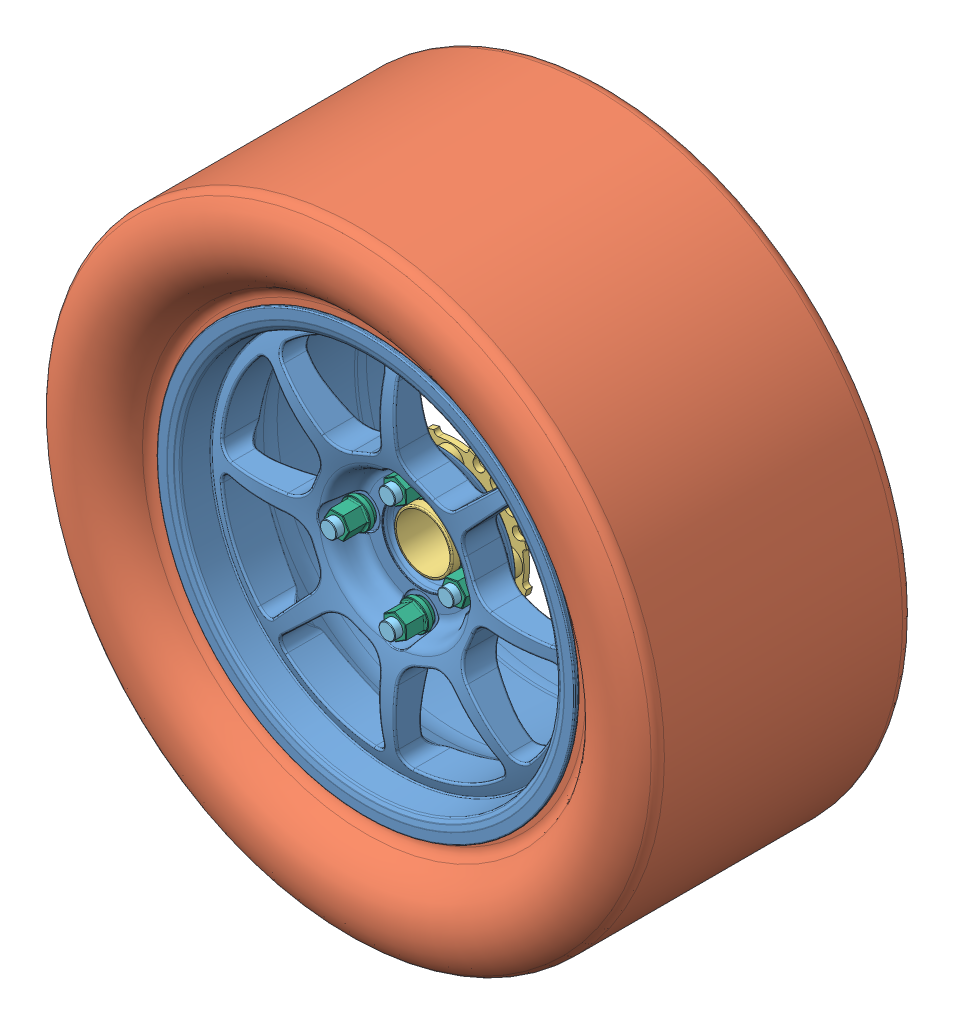
SolidWorks assembly PUTM-S-SR-WT-Hub_Assembly, configuration Default. Lengths in mm.
Overall size (534.5 534.5 238.76).
12 component instances, 6 part files, 26 mates.
Components (placement in the parent):
- PUTM-S-WT-Wheel_Rim-1: PUTM-S-WT-Wheel_Rim [Domyślna] at (27.2371 -11.0021 -114.5898) x (0 0 -1) z (1 0.000237 0) size (189.8 356.77 356.77)
- PUTM-S-SR-WT-Tire-1: PUTM-S-SR-WT-Tire [Default] at (27.2371 -11.0021 -144.4518) x (0.999763 0.021752 0) z (0.021752 -0.999763 0) size (523.24 238.76 523.24)
- PUTM-S-SR-WT-Hub-1: PUTM-S-SR-WT-Hub [Domyślna] at (27.2371 -11.0021 -98.5898) x (0.000237 -1 0) z (0 0 1) size (128.55 128.55 119.65)
- PUTM-S-SR-WT-WH-tripod_housing_2mm-1: PUTM-S-SR-WT-WH-tripod_housing_2mm [Domyślna] at (27.2371 -11.0021 -197.7398) x (-0.999996 0.00292 0) z (0.00292 0.999996 0) size (55.96 51.5 61.23)
- PUTM-S-SF-WT-WH-wheel_stud-1: PUTM-S-SF-WT-WH-wheel_stud [Domyślna] at (-22.7629 -11.014 -129.5898) x (0 0 1) z (0.77693 0.629587 0) size (62 20 20)
- PUTM-S-SF-WT-WH-wheel_stud-2: PUTM-S-SF-WT-WH-wheel_stud [Domyślna] at (27.249 -61.0021 -129.5898) x (0 0 1) z (-0.990977 0.134035 0) size (62 20 20)
- PUTM-S-SF-WT-WH-wheel_stud-3: PUTM-S-SF-WT-WH-wheel_stud [Domyślna] at (27.2253 38.9979 -129.5898) x (0 0 1) z (-0.993487 -0.113947 0) size (62 20 20)
- PUTM-S-SF-WT-WH-wheel_stud-4: PUTM-S-SF-WT-WH-wheel_stud [Domyślna] at (77.2371 -10.9903 -129.5898) x (0 0 1) z (-0.856009 -0.516961 0) size (62 20 20)
- PUTM-S-WT-WheelNut-1: PUTM-S-WT-WheelNut [Domyślna] at (27.2253 38.9979 -74.3253) x (-0.999238 -0.039031 0) z (0.039031 -0.999238 0) size (25 27 25)
- PUTM-S-WT-WheelNut-2: PUTM-S-WT-WheelNut [Domyślna] at (77.2371 -10.9903 -74.3253) x (0.748262 0.663403 0) z (-0.663403 0.748262 0) size (25 27 25)
- PUTM-S-WT-WheelNut-3: PUTM-S-WT-WheelNut [Domyślna] at (27.249 -61.0021 -74.3253) x (-0.999238 -0.039031 0) z (0.039031 -0.999238 0) size (25 27 25)
- PUTM-S-WT-WheelNut-4: PUTM-S-WT-WheelNut [Domyślna] at (-22.7629 -11.014 -74.5933) x (0.864346 0.502898 0) z (-0.502898 0.864346 0) size (25 27 25)
Mates (geometry in assembly coordinates):
- Wspólnie27: coincident anti-aligned: plane of PUTM-S-SR-WT-Hub-1 through (27.2371 -11.0021 -153.2398) normal (0 0 -1); plane of PUTM-S-SR-WT-WH-tripod_housing_2mm-1 through (17.0872 -10.9725 -153.2398) normal (0 0 1)
- Koncentryczne2: concentric aligned: cylinder of PUTM-S-SR-WT-Hub-1 through (27.2371 -11.0021 -153.2398) axis (0 0 -1) radius 31; cylinder of PUTM-S-SR-WT-WH-tripod_housing_2mm-1 through (27.2371 -11.0021 -153.2398) axis (0 0 -1) radius 29
- Koncentryczne5: concentric aligned: circle of PUTM-S-SR-WT-Tire-1; circle of PUTM-S-SR-WT-Hub-1
- Wspólnie37: coincident anti-aligned: plane of PUTM-S-SR-WT-Hub-1 through (27.2371 -11.0021 -153.2398) normal (0 0 -1); plane of PUTM-S-SR-WT-WH-tripod_housing_2mm-1 through (17.0872 -10.9725 -153.2398) normal (0 0 1)
- Koncentryczne6: concentric anti-aligned: cylinder of PUTM-S-SR-WT-Hub-1 through (27.2253 38.9979 -112.5898) axis (0 0 -1) radius 6.05; cylinder of PUTM-S-SF-WT-WH-wheel_stud-3 through (27.2253 38.9979 -67.5898) axis (0 0 1) radius 7
- Koncentryczne7: concentric anti-aligned: cylinder of PUTM-S-SR-WT-Hub-1 through (77.2371 -10.9903 -112.5898) axis (0 0 -1) radius 6.05; cylinder of PUTM-S-SF-WT-WH-wheel_stud-4 through (77.2371 -10.9903 -67.5898) axis (0 0 1) radius 7
- Koncentryczne8: concentric anti-aligned: cylinder of PUTM-S-SR-WT-Hub-1 through (27.249 -61.0021 -112.5898) axis (0 0 -1) radius 6.05; cylinder of PUTM-S-SF-WT-WH-wheel_stud-2 through (27.249 -61.0021 -67.5898) axis (0 0 1) radius 7
- Wspólnie38: coincident anti-aligned: plane of PUTM-S-SR-WT-Hub-1 through (27.2253 38.9979 -124.5898) normal (0 0 -1); plane of PUTM-S-SF-WT-WH-wheel_stud-3 through (26.0858 48.9327 -124.5898) normal (0 0 1)
- Wspólnie39: coincident anti-aligned: plane of PUTM-S-SR-WT-Hub-1 through (-22.7629 -11.014 -124.5898) normal (0 0 -1); plane of PUTM-S-SF-WT-WH-wheel_stud-1 through (-16.467 -18.7833 -124.5898) normal (0 0 1)
- Koncentryczne10: concentric anti-aligned: cylinder of PUTM-S-SR-WT-Hub-1 through (-22.7629 -11.014 -112.5898) axis (0 0 -1) radius 6.05; cylinder of PUTM-S-SF-WT-WH-wheel_stud-1 through (-22.7629 -11.014 -67.5898) axis (0 0 1) radius 7
- Wspólnie40: coincident anti-aligned: plane of PUTM-S-SR-WT-Hub-1 through (27.249 -61.0021 -124.5898) normal (0 0 -1); plane of PUTM-S-SF-WT-WH-wheel_stud-2 through (28.5893 -51.0924 -124.5898) normal (0 0 1)
- Wspólnie41: coincident anti-aligned: plane of PUTM-S-SR-WT-Hub-1 through (77.2371 -10.9903 -124.5898) normal (0 0 -1); plane of PUTM-S-SF-WT-WH-wheel_stud-4 through (72.0675 -2.4302 -124.5898) normal (0 0 1)
- Koncentryczne11: concentric aligned: cone of PUTM-S-WT-Wheel_Rim-1 through (27.2371 -11.0021 -127.4822) axis (0 0 1); cylinder of PUTM-S-SR-WT-Hub-1 through (27.2371 -11.0021 -98.5898) axis (0 0 1) radius 34.5
- Koncentryczne12: concentric anti-aligned: cylinder of PUTM-S-WT-Wheel_Rim-1 through (77.2371 -10.9903 -49.5508) axis (0 0 -1) radius 7.5; cylinder of PUTM-S-SF-WT-WH-wheel_stud-4 through (77.2371 -10.9903 -67.5898) axis (0 0 1) radius 7
- Wspólnie42: coincident anti-aligned: plane of PUTM-S-WT-Wheel_Rim-1 through (-0.192 -11.0086 -114.5898) normal (0 0 -1); plane of PUTM-S-SR-WT-Hub-1 through (27.2371 -11.0021 -114.5898) normal (0 0 1)
- Wspólnie43: coincident anti-aligned: plane of PUTM-S-WT-Wheel_Rim-1 through (-147.1497 -11.0435 -233.3518) normal (0 0 1); plane of PUTM-S-SR-WT-Tire-1 through (23.285 170.6499 -233.3518) normal (0 0 -1)
- Koncentryczne14: concentric anti-aligned: circle of PUTM-S-SF-WT-WH-wheel_stud-2; cylinder of PUTM-S-SR-WT-WH-IISO 7040-M10_WHEEL [FABORY]-1 through (27.249 -61.0021 -86.8468) axis (0 0 -1) radius 5
- Koncentryczne15: concentric aligned: cylinder of PUTM-S-SF-WT-WH-wheel_stud-3 through (27.2253 38.9979 -67.5898) axis (0 0 1) radius 7; cylinder of PUTM-S-WT-WheelNut-1 through (27.2253 38.9979 -74.3253) axis (0 0 1) radius 6
- Koncentryczne16: concentric aligned: cylinder of PUTM-S-SF-WT-WH-wheel_stud-2 through (27.249 -61.0021 -67.5898) axis (0 0 1) radius 7; circle of PUTM-S-WT-WheelNut-3
- Koncentryczne17: concentric aligned: cylinder of PUTM-S-SF-WT-WH-wheel_stud-4 through (77.2371 -10.9903 -67.5898) axis (0 0 1) radius 7; cylinder of PUTM-S-WT-WheelNut-2 through (77.2371 -10.9903 -74.3253) axis (0 0 1) radius 6
- Koncentryczne18: concentric aligned: cylinder of PUTM-S-SF-WT-WH-wheel_stud-3 through (27.2253 38.9979 -67.5898) axis (0 0 1) radius 7; cylinder of PUTM-S-WT-WheelNut-1 through (27.2253 38.9979 -74.3253) axis (0 0 1) radius 6
- Koncentryczne19: concentric aligned: cylinder of PUTM-S-SF-WT-WH-wheel_stud-1 through (-22.7629 -11.014 -67.5898) axis (0 0 1) radius 7; cylinder of PUTM-S-WT-WheelNut-4 through (-22.7629 -11.014 -74.5933) axis (0 0 1) radius 6
- Wspólnie45: coincident aligned: circle of PUTM-S-WT-Wheel_Rim-1; cone of PUTM-S-WT-WheelNut-3 through (27.249 -61.0021 -101.3253) axis (0 0 -1)
- Wspólnie46: coincident aligned: circle of PUTM-S-WT-Wheel_Rim-1; cone of PUTM-S-WT-WheelNut-2 through (77.2371 -10.9903 -101.3253) axis (0 0 -1)
- Wspólnie47: coincident aligned: circle of PUTM-S-WT-Wheel_Rim-1; cone of PUTM-S-WT-WheelNut-1 through (27.2253 38.9979 -101.3253) axis (0 0 -1)
- Wspólnie48: coincident anti-aligned: circle of PUTM-S-WT-Wheel_Rim-1; cone of PUTM-S-WT-WheelNut-4 through (-22.7629 -11.014 -101.5933) axis (0 0 -1)
